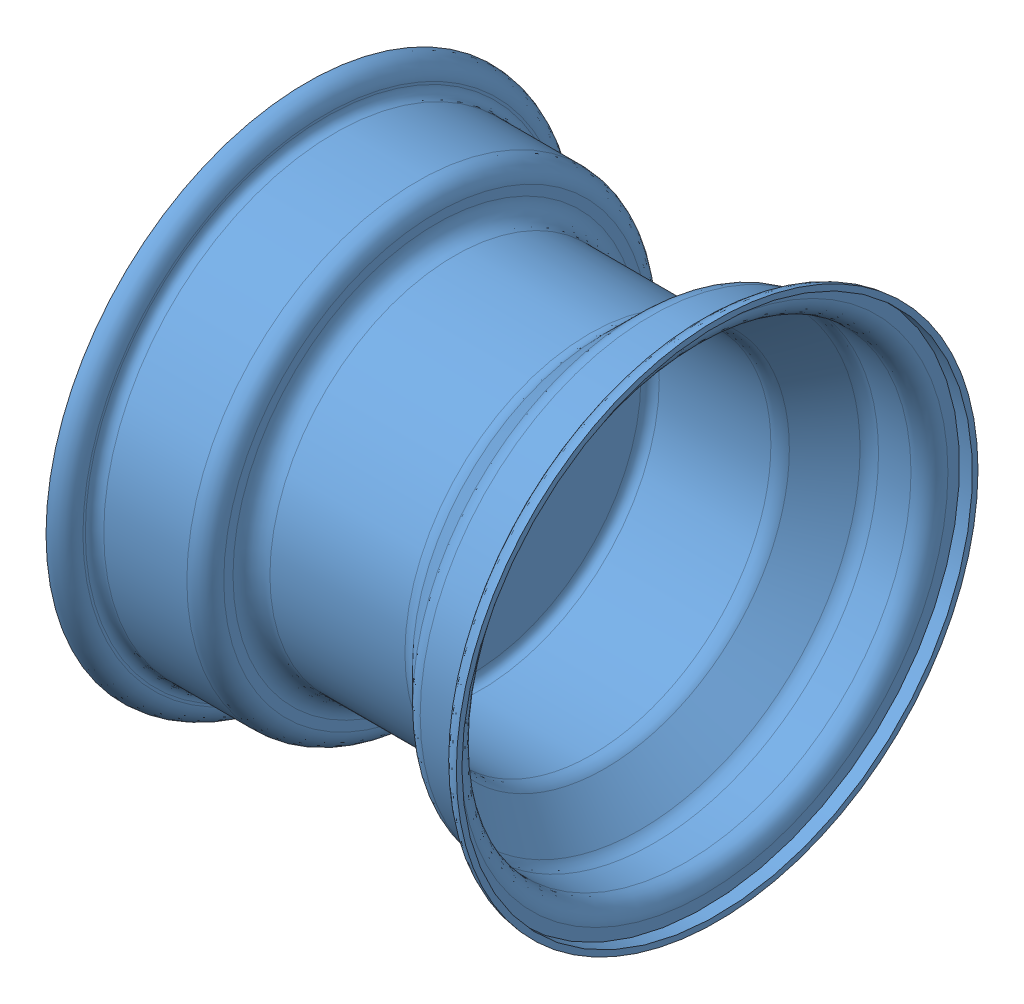
SolidWorks assembly Rin y Masa, configuration Predeterminado. Lengths in mm.
Overall size (222.25 282.58 282.58).
4 component instances, 4 part files, 13 mates.
Components (placement in the parent):
- Rin 10 plata-2: Rin 10 plata [Predeterminado] at origin size (222.25 282.58 282.58)
- Maza_Chevy-2: Maza_Chevy [Masa_Trasera] at (-27.63 0 0) x (-1 0 0) z (0 -1 0) size (76 120 120)
- Pieza5-1: Pieza5 [Predeterminado] x (0 0 -1) z (1 0 0)
- Espaciador_trasero-1: Espaciador_trasero [Predeterminado] at (-28.58 0 0) x (0 0 -1) z (1 0 0) size (140 140 25.4)
Mates (geometry in assembly coordinates):
- Concéntrica3: concentric aligned: cylinder of Rin 10 plata-2 through (-28.575 0 0) axis (1 0 0) radius 44.45; cylinder of Maza_Chevy-2 through (-27.63 0 0) axis (1 0 0) radius 13.5
- EnPosición3: in place: plane of Pieza5-1 through (0 0 0) normal (1 0 0); moOrthogonalPlaneRef_w of Pieza5-1 through (0 0 0) normal (0 1 0); plane of Pieza5-1 through (0 0 0) normal (0 0 -1); unknown of Pieza5-1
- Coincidente9: coincident aligned: 
- Coincidente10: coincident aligned: plane of Pieza5^Rin y Masa-1 through (0 0 0) normal (0 1 0)
- Coincidente11: coincident anti-aligned: plane of Pieza5^Rin y Masa-1 through (0 0 0) normal (0 0 -1)
- EnPosición4: in place: plane of Espaciador_trasero-1 through (-28.58 0 0) normal (1 0 0); plane of Espaciador_trasero-1 through (-28.58 0 0) normal (0 1 0); plane of Espaciador_trasero-1 through (-28.58 0 0) normal (0 0 -1); unknown of Espaciador_trasero-1
- Coincidente12: coincident aligned: 
- Coincidente13: coincident aligned: plane of Pieza6^Rin y Masa-1 through (-28.58 0 0) normal (0 1 0)
- Coincidente14: coincident anti-aligned: plane of Pieza6^Rin y Masa-1 through (-28.58 0 0) normal (0 0 -1)
- Concéntrica4: concentric aligned: cylinder of Rin 10 plata-2 through (-28.575 0 0) axis (1 0 0) radius 44.45; cylinder of Espaciador_trasero-1 through (-47.63 0 0) axis (1 0 0) radius 28.5
- Coincidente15: coincident anti-aligned: plane of Maza_Chevy-2 through (-47.63 0 -60) normal (1 0 0); plane of Espaciador_trasero-1 through (-47.63 0 0) normal (-1 0 0)
- Concéntrica7: concentric anti-aligned: cylinder of Rin 10 plata-2 through (-28.575 -54 0) axis (1 0 0) radius 6; cylinder of Espaciador_trasero-1 through (-3.8313 -54 0) axis (-1 0 0) radius 8.75
- Concéntrica8: concentric anti-aligned: cylinder of Maza_Chevy-2 through (-27.63 -35.0371 35.0371) axis (-1 0 0) radius 5.25; cylinder of Espaciador_trasero-1 through (-47.63 -35.0371 35.0371) axis (1 0 0) radius 6.5
